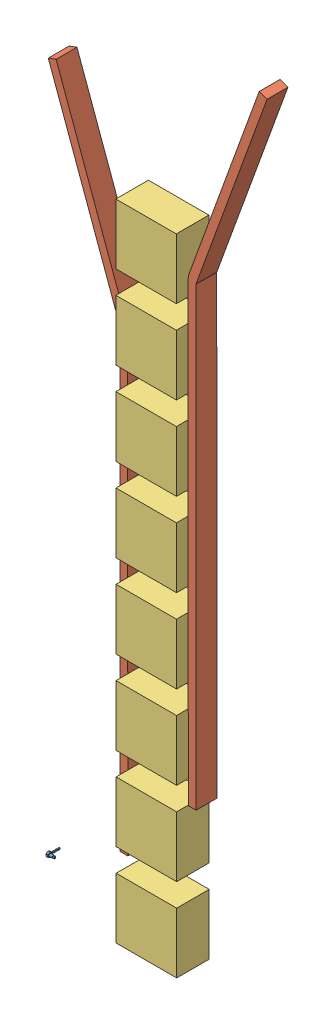
SolidWorks assembly conveyor_145x1200_complete, configuration Domyślna. Lengths in mm.
Overall size (1226.45 1912.39 80.4).
13 component instances, 4 part files, 6 mates.
Components (placement in the parent):
- Belt Conveyor.step-1: Belt Conveyor.step [Domyślna] at (-64.4362 912.0124 3281.4657) (suppressed, hidden)
- FU-R67TZ-1: FU-R67TZ [Default] at (-303.4136 -1473.5631 3846.1036) size (16.81 11.5 30)
- Część191^conveyor_145x1200_complete-1: Część191^conveyor_145x1200_complete [Domyślna] at origin (virtual)
- prowadnica-1: prowadnica [Domyślna] at (138.2941 151.1302 3823.5787) x (-0.34202 -0.939692 -0.000577) z (0 -0.000614 1) size (1532.53 393.44 50)
- prowadnica-2: prowadnica [Domyślna] at (-196.5098 -25.754 3873.4701) x (0.34202 -0.939692 -0.000577) z (0 0.000614 -1) size (1532.53 393.44 50)
- blk-145x145-1: blk-145x145 [Default] at (-556.6079 -1450.3639 3822.5957) x (1 0 0) z (0 -0.000614 1) size (145 145 78)
- blk-145x145-4: blk-145x145 [Default] at (-556.6079 -1250.364 3822.7185) x (1 0 0) z (0 -0.000614 1) size (145 145 78)
- blk-145x145-5: blk-145x145 [Default] at (-556.6079 -1050.364 3822.8412) x (1 0 0) z (0 -0.000614 1) size (145 145 78)
- blk-145x145-6: blk-145x145 [Default] at (-556.6079 -850.364 3822.964) x (1 0 0) z (0 -0.000614 1) size (145 145 78)
- blk-145x145-7: blk-145x145 [Default] at (-556.6079 -650.3641 3823.0867) x (1 0 0) z (0 -0.000614 1) size (145 145 78)
- blk-145x145-8: blk-145x145 [Default] at (-556.6079 -450.3641 3823.2095) x (1 0 0) z (0 -0.000614 1) size (145 145 78)
- blk-145x145-9: blk-145x145 [Default] at (-556.6079 -250.3642 3823.3323) x (1 0 0) z (0 -0.000614 1) size (145 145 78)
- blk-145x145-10: blk-145x145 [Default] at (-556.6079 -50.3642 3823.455) x (1 0 0) z (0 -0.000614 1) size (145 145 78)
Mates (geometry in assembly coordinates):
- Wspólnie3: coincident anti-aligned: plane of Belt Conveyor.step-1/8260K11_Mounted Bearing with Three-Bolt Flange.step-1/8260K11_Mounted Bearing with Three-Bolt Flange(Mirror) (3).step-1/8260K11_Mounted Bearing with Three-Bolt Flange(Mirror) (3)-14.step-1 through (-311.3672 -1378.6233 3821.1036) normal (0 0 1); plane of FU-R67TZ-1 through (-316.8136 -1474.6641 3821.1036) normal (0 0 -1)
- Wspólnie5: coincident anti-aligned: plane of Belt Conveyor.step-1/Belt doang v4.step-1 through (218.6326 -1543.8403 3822.5384) normal (0 -0.000614 1); plane of prowadnica-1 through (138.2941 151.1302 3823.5787) normal (0 0.000614 -1)
- Wspólnie7: coincident anti-aligned: plane of Belt Conveyor.step-1/Belt doang v4.step-1 through (218.6326 -1543.8403 3822.5384) normal (0 -0.000614 1); plane of prowadnica-2 through (-196.5098 -25.7233 3823.4701) normal (0 0.000614 -1)
- Wspólnie8: coincident anti-aligned: plane of Belt Conveyor.step-1/Belt doang v4.step-1 through (218.6326 -1543.8403 3822.5384) normal (0 -0.000614 1); plane of blk-145x145-1 through (43.3921 -1522.8639 3822.5512) normal (0 0.000614 -1)
- Wspólnie9: coincident anti-aligned: plane of prowadnica-2 through (-101.6079 -257.2262 3823.328) normal (1 0 0); plane of blk-145x145-1 through (-101.6079 -1377.9118 3900.6402) normal (-1 0 0)
- Wspólnie10: coincident: line of prowadnica-1 through (43.3921 -89.2197 3873.4312) axis (0 -1 -0.000614); plane of blk-145x145-1 through (43.3921 -1377.9118 3900.6402) normal (1 0 0)
